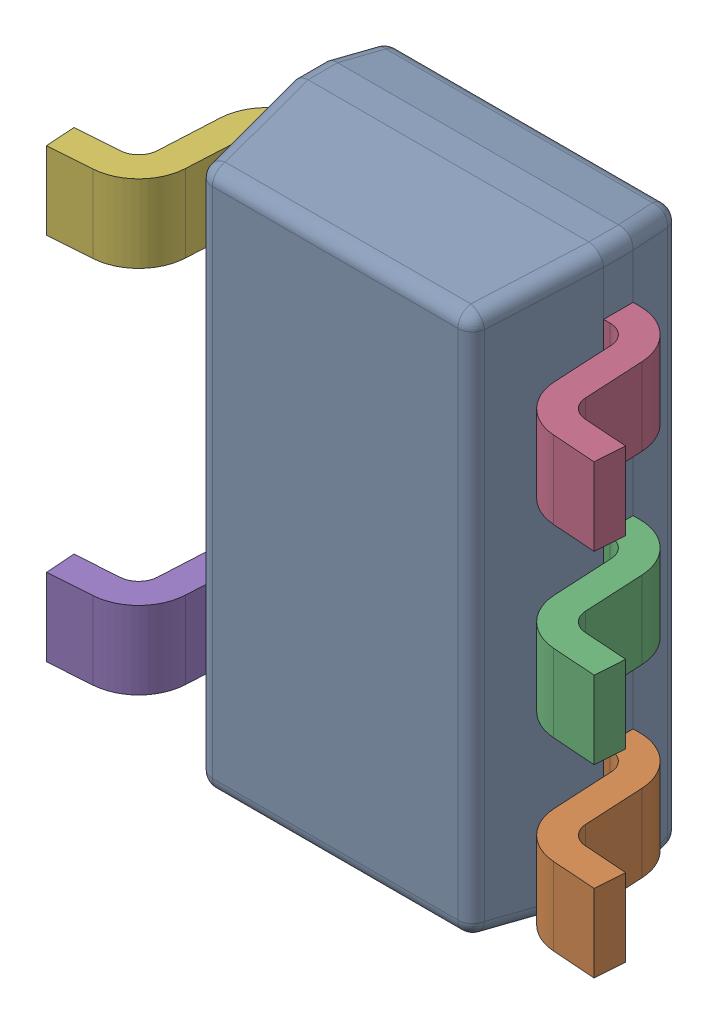
SolidWorks assembly U405PCB, configuration Default. Lengths in mm.
Overall size (2.85 2.93 1.09).
7 component instances, 2 part files, 0 mates.
Components (placement in the parent):
- DBV0005AaksMF05A-1: DBV0005AaksMF05A [Default] at (115.9001 94.9999 -2.4638) x (0 -1 0) z (1 0 0) size (2.93 1.09 2.85)
  - BODY_MF05A-1: BODY_MF05A [Default] at origin size (2.93 1.02 1.6)
  - LEAD_MF05F-1: LEAD_MF05F [Default] at (0.9525 -0.6096 0.9546) size (0.4 0.81 0.62)
  - LEAD_MF05F-2: LEAD_MF05F [Default] at (0 -0.6096 0.9546) size (0.4 0.81 0.62)
  - LEAD_MF05F-3: LEAD_MF05F [Default] at (-0.9525 -0.6096 0.9546) size (0.4 0.81 0.62)
  - LEAD_MF05F-4: LEAD_MF05F [Default] at (0.9525 -0.6096 -0.9546) x (-1 0 0) z (0 0 -1) size (0.4 0.81 0.62)
  - LEAD_MF05F-5: LEAD_MF05F [Default] at (-0.9525 -0.6096 -0.9546) x (-1 0 0) z (0 0 -1) size (0.4 0.81 0.62)
